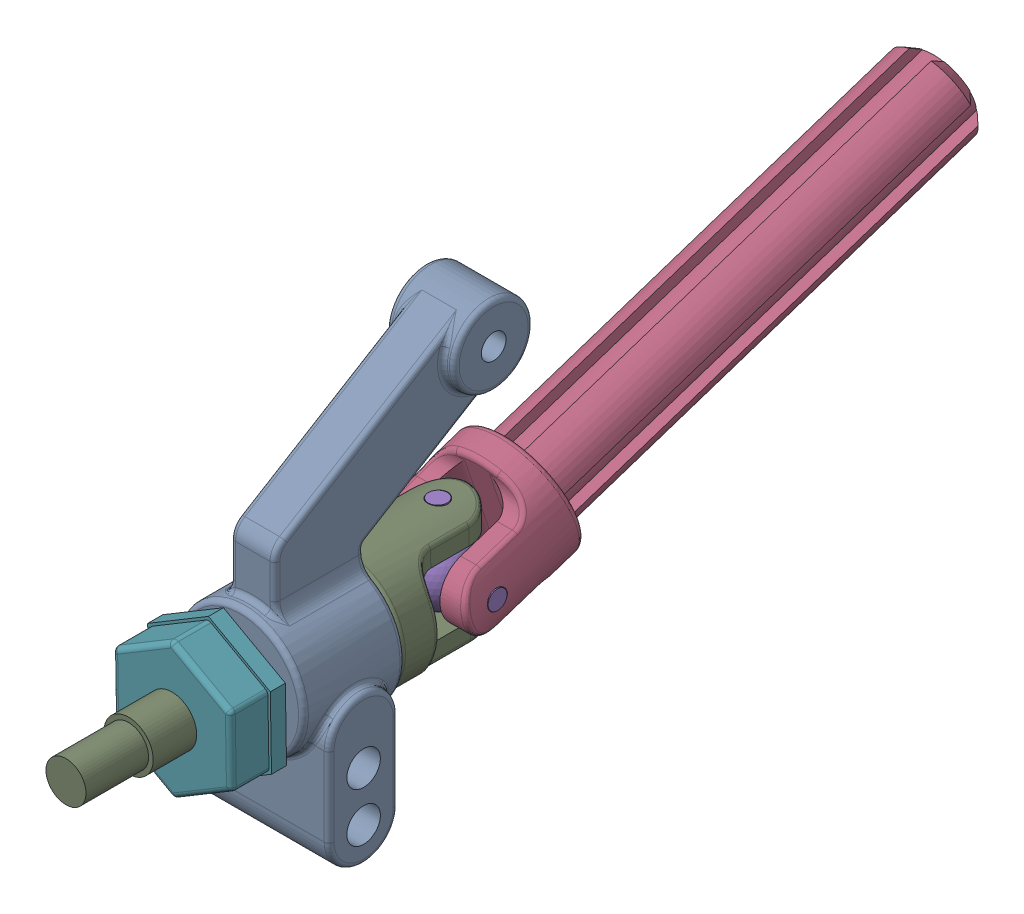
SolidWorks assembly rear spindle(Default-_flexible2), configuration Default. Lengths in mm.
Overall size (14.8 39 90.91).
9 component instances, 8 part files, 0 mates.
Components (placement in the parent):
- 3752-1: 3752 [Default] at origin size (14.8 39 26.3)
- 1675-1: 1675 [Default] at (0 0 -3.65) x (-0.905715 -0.423888 0) z (0 0 1) size (8 8 3)
- 1675-2: 1675 [Default] at (0 0 3.65) x (-0.99623 -0.086749 0) z (0 0 1) size (8 8 3)
- 1951A-1: 1951A [Default] at (0 2.7756 -23.4548) x (-0.017463 0.949691 0.312701) z (0 -0.312748 0.949836) size (12 12 57)
- 1951B-1: 1951B [Default] at (0 0 -15.025) x (0.999848 0.016587 0.005462) z (0.005461 0.000091 -0.999985) size (12 12 6.5)
- 2754-1: 2754 [Default] at (0 0 7.2) x (-0.016588 0.999862 0) z (-0.997685 -0.016552 -0.065956) size (9.65 1.98 1.98)
- 3654-1: 3654 [Default] at (0 0 8.2287) x (0.016588 -0.999862 0) z (0 0 1) size (14.37 12.45 5.84)
- 1985-1: 1985 [Default] at (0 0 5.4) x (-0.944178 -0.329436 0) z (0 0 1) size (8 8 0.5)
- 1951C-1: 1951C [Default] at (0 0 -5.15) x (-0.999862 -0.016588 0) z (0 0 -1) size (12 12 40.95)
